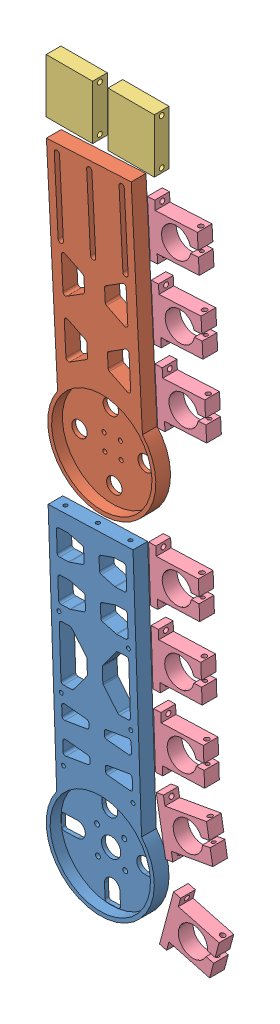
SolidWorks assembly Assem3, configuration Layout1[6061-T6 (SS)_9.525mm_Qnty1]. Lengths in mm.
Overall size (508 508 9.53).
12 component instances, 4 part files, 0 mates.
Components (placement in the parent):
- Roll Arm-1: Roll Arm [Default] at (45 45.0642 -9.525) x (0.999391 0.034899 0) z (0 0 1) size (70 215 9.53)
- Yaw Arm-1: Yaw Arm [Default] at (45.9635 270.4526 -9.525) x (0.99863 0.052336 0) z (0.052336 -0.99863 0) size (70 9.53 195)
- Spacer-1: Spacer [Default] at (40 458.1 -4.7625) x (0 -1 0) z (0 0 -1) size (35 30 9.53)
- Spacer-2: Spacer [Default] at (80 459.3 -4.7625) x (0 -1 0) z (0 0 -1) size (35 30 9.53)
- tclamp-1: tclamp [Default] at (94.1494 412.2752 -9.525) x (0.052336 -0.99863 0) z (0 0 1) size (35 32.06 9.53)
- tclamp-2: tclamp [Default] at (94.6161 218.4775 -9.525) x (0.034899 -0.999391 0) z (0 0 1) size (35 32.06 9.53)
- tclamp-3: tclamp [Default] at (96.2161 172.4775 -9.525) x (0.034899 -0.999391 0) z (0 0 1) size (35 32.06 9.53)
- tclamp-4: tclamp [Default] at (96.5494 366.4752 -9.525) x (0.052336 -0.99863 0) z (0 0 1) size (35 32.06 9.53)
- tclamp-5: tclamp [Default] at (97.8161 126.6775 -9.525) x (0.034899 -0.999391 0) z (0 0 1) size (35 32.06 9.53)
- tclamp-6: tclamp [Default] at (98.9494 320.6752 -9.525) x (0.052336 -0.99863 0) z (0 0 1) size (35 32.06 9.53)
- tclamp-7: tclamp [Default] at (101.6961 83.2215 -9.525) x (0.173648 -0.984808 0) z (0 0 1) size (35 32.06 9.53)
- tclamp-8: tclamp [Default] at (105.0175 25.7455 -9.525) x (-0.258819 -0.965926 0) z (0 0 1) size (35 32.06 9.53)
